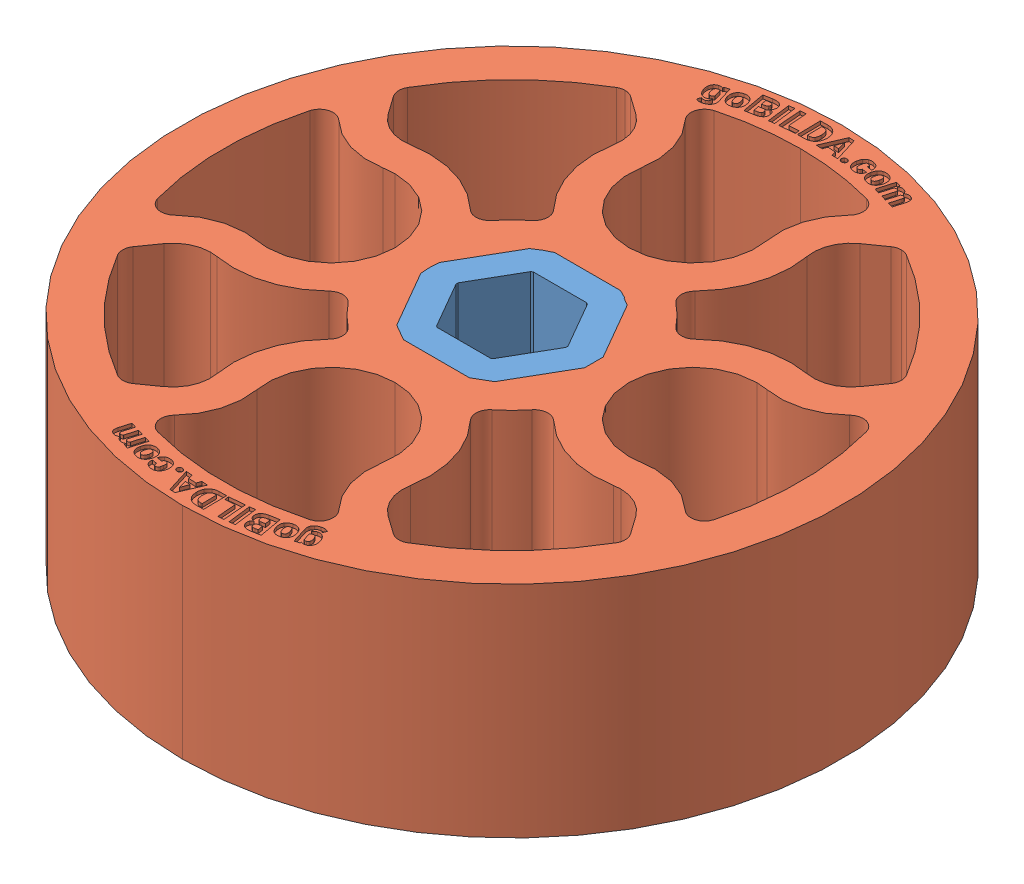
SolidWorks assembly 48mm Gecko Wheels 3613-4008-0048, configuration Default. Lengths in mm.
Overall size (48 16 48).
2 component instances, 2 part files, 0 mates.
Components (placement in the parent):
- 3613-4008-0048 Core.STEP-1: 3613-4008-0048 Core.STEP [Default] at (-59.4511 7.7168 20.6938) size (12 16 11)
- 3613-4008-0048 Rubber.STEP-1: 3613-4008-0048 Rubber.STEP [Default] at (-59.4511 7.7168 20.6938) size (48 16 48)
